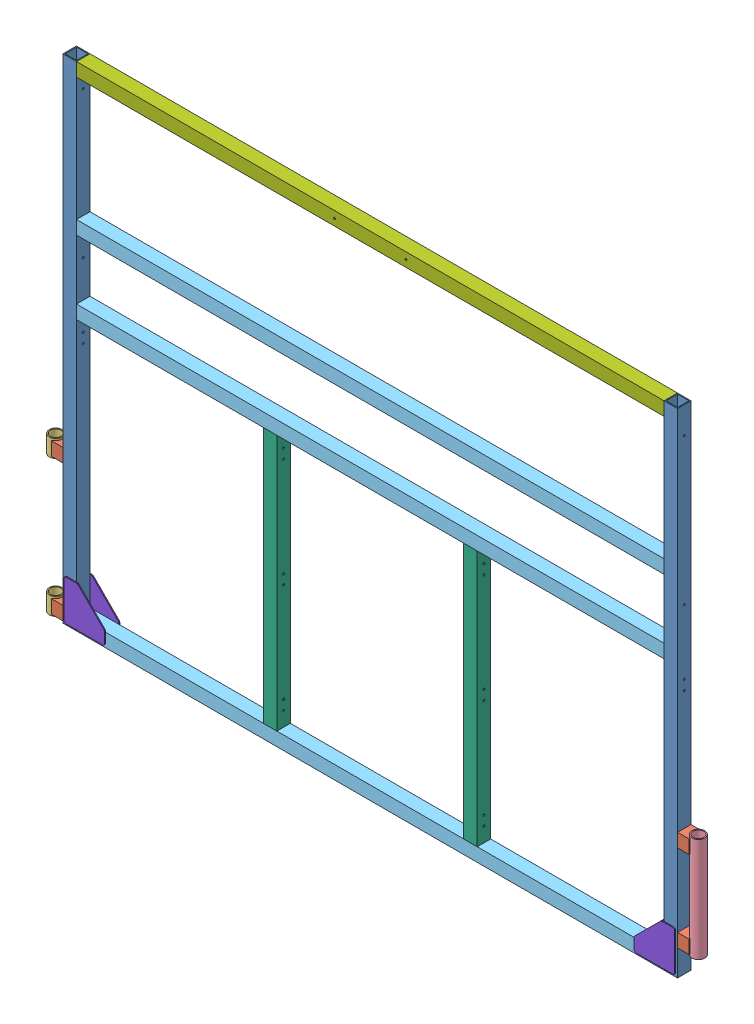
SolidWorks assembly GE-25001, configuration Default. Lengths in mm.
Overall size (2163.1 1625.6 50.8).
19 component instances, 8 part files, 45 mates.
Components (placement in the parent):
- GE-25001-01-1: GE-25001-01 [Default] at (-1012.825 1625.6 -22.225) x (0 -1 0) z (-1 0 0) size (1625.6 44.45 44.45)
- GE-25001-04-1: GE-25001-04 [Default] at (-1012.825 50.8 -22.225) x (-1 0 0) z (0 1 0) size (38.1 44.45 44.45)
- GE-25001-05-2: GE-25001-05 [Default] at (-1059.307 450.85 0) x (0.99576 0 -0.091988) z (0.091988 0 0.99576) size (42.16 57.15 42.16)
- GE-25001-04-2: GE-25001-04 [Default] at (-1012.825 501.65 -22.225) x (-1 0 0) z (0 1 0) size (38.1 44.45 44.45)
- GE-25001-01-2: GE-25001-01 [Default] at (968.375 1625.6 -22.225) x (0 -1 0) z (-1 0 0) size (1625.6 44.45 44.45)
- GE-25001-04-3: GE-25001-04 [Default] at (1012.825 130.175 22.225) x (1 0 0) z (0 1 0) size (38.1 44.45 44.45)
- GE-25001-04-4: GE-25001-04 [Default] at (1012.825 415.925 22.225) x (1 0 0) z (0 1 0) size (38.1 44.45 44.45)
- GE-25001-06-1: GE-25001-06 [Default] at (1059.307 79.375 0) x (-0.999745 0 0.022564) z (-0.022564 0 -0.999745) size (42.16 342.9 42.16)
- GE-25001-03-1: GE-25001-03 [Default] at (-968.375 889 22.225) size (1936.75 44.45 44.45)
- GE-25001-03-2: GE-25001-03 [Default] at (-968.375 0 22.225) size (1936.75 44.45 44.45)
- GE-25001-03-4: GE-25001-03 [Default] at (-968.375 1130.3 22.225) size (1936.75 44.45 44.45)
- GE-25001-02-1: GE-25001-02 [Default] at (-352.425 44.45 -22.225) x (0 0 1) z (-1 0 0) size (44.45 844.55 44.45)
- GE-25001-02-2: GE-25001-02 [Default] at (307.975 44.45 -22.225) x (0 0 1) z (-1 0 0) size (44.45 844.55 44.45)
- GE-25001-05-3: GE-25001-05 [Default] at (-1059.307 0 0) x (-1 0 0) z (0 0 -1) size (42.16 57.15 42.16)
- GE-25001-07-1: GE-25001-07 [Default] at (-968.375 1581.15 22.225) size (1936.75 44.45 44.45)
- GE-25001-08-1: GE-25001-08 [Default] at (1006.475 6.35 -25.4) x (0 1 0) z (1 0 0) size (133.35 3.17 133.35)
- GE-25001-08-2: GE-25001-08 [Default] at (1006.475 6.35 22.225) x (0 1 0) z (1 0 0) size (133.35 3.17 133.35)
- GE-25001-08-3: GE-25001-08 [Default] at (-1006.475 6.35 -22.225) x (0 1 0) z (-1 0 0) size (133.35 3.17 133.35)
- GE-25001-08-4: GE-25001-08 [Default] at (-1006.475 6.35 25.4) x (0 1 0) z (-1 0 0) size (133.35 3.17 133.35)
Mates (geometry in assembly coordinates):
- Coincident4: coincident aligned: plane of GE-24001-01-1 through (-1012.825 0 22.225) normal (0 0 1); plane of GE-24001-04-1 through (-1050.925 50.8 22.225) normal (0 0 1)
- Distance1: distance = 6.35 mm aligned: plane of Front Frame Pin Holders-1 through (-1050.925 6.35 -22.225) normal (0 -1 0); plane of GE-24001-01-1 through (-1012.825 0 -22.225) normal (0 -1 0)
- Coincident6: coincident anti-aligned: plane of GE-24001-01-1 through (-1012.825 0 -22.225) normal (-1 0 0); plane of GE-24001-04-1 through (-1012.825 50.8 -22.225) normal (1 0 0)
- Coincident9: coincident aligned: plane of GE-24001-04-1 through (-1050.925 50.8 22.225) normal (0 0 1); plane of GE-24001-04-2 through (-1050.925 501.65 22.225) normal (0 0 1)
- Coincident10: coincident anti-aligned: plane of GE-24001-01-1 through (-1012.825 0 -22.225) normal (-1 0 0); plane of GE-24001-04-2 through (-1012.825 501.65 -22.225) normal (1 0 0)
- Coincident12: coincident aligned: plane of GE-24001-01-1 through (-1012.825 0 22.225) normal (0 0 1); plane of GE-24001-01-2 through (968.375 0 22.225) normal (0 0 1)
- Coincident13: coincident aligned: plane of GE-24001-01-1 through (-1012.825 1625.6 -22.225) normal (0 1 0); plane of GE-24001-01-2 through (968.375 1625.6 -22.225) normal (0 1 0)
- Coincident14: coincident aligned: plane of GE-24001-01-2 through (968.375 0 -22.225) normal (0 0 -1); plane of GE-24001-04-4 through (1050.925 415.925 -22.225) normal (0 0 -1)
- Coincident15: coincident anti-aligned: plane of GE-24001-01-2 through (1012.825 0 -22.225) normal (1 0 0); plane of GE-24001-04-4 through (1012.825 415.925 22.225) normal (-1 0 0)
- Coincident16: coincident anti-aligned: plane of GE-24001-01-2 through (1012.825 0 -22.225) normal (1 0 0); plane of GE-24001-04-3 through (1012.825 130.175 22.225) normal (-1 0 0)
- Coincident18: coincident aligned: plane of GE-24001-04-3 through (1050.925 130.175 22.225) normal (0 0 1); plane of GE-24001-04-4 through (1050.925 415.925 22.225) normal (0 0 1)
- Distance4: distance = 79.375 mm aligned: plane of GE-24001-01-2 through (968.375 0 -22.225) normal (0 -1 0); plane of GE-24001-06-1 through (1059.307 79.375 0) normal (0 -1 0)
- Distance5: distance = 6.35 mm aligned: plane of Front Frame Pin Holders-3 through (1050.925 85.725 22.225) normal (0 -1 0); plane of GE-24001-06-1 through (1059.307 79.375 0) normal (0 -1 0)
- Concentric3: concentric anti-aligned: cylinder of GE-24001-04-3 through (1059.307 85.725 0) axis (0 1 0) radius 21.082; cylinder of GE-24001-06-1 through (1059.307 422.275 0) axis (0 -1 0) radius 21.082
- Distance6: distance = 6.35 mm aligned: plane of Front Frame Pin Holders-4 through (1050.925 415.925 22.225) normal (0 1 0); plane of GE-24001-06-1 through (1059.307 422.275 0) normal (0 1 0)
- Coincident22: coincident aligned: plane of GE-24001-03-1 through (968.375 889 22.225) normal (0 0 1); plane of GE-24001-03-4 through (968.375 1130.3 22.225) normal (0 0 1)
- Coincident25: coincident aligned: plane of GE-24001-01-1 through (-1012.825 0 22.225) normal (0 0 1); plane of GE-24001-03-2 through (968.375 0 22.225) normal (0 0 1)
- Coincident26: coincident aligned: plane of GE-24001-01-1 through (-1012.825 0 -22.225) normal (0 -1 0); plane of GE-24001-03-2 through (968.375 0 22.225) normal (0 -1 0)
- Coincident27: coincident anti-aligned: plane of GE-24001-01-1 through (-968.375 0 -22.225) normal (1 0 0); plane of GE-24001-03-2 through (-968.375 0 22.225) normal (-1 0 0)
- Coincident28: coincident anti-aligned: plane of GE-24001-01-2 through (968.375 0 -22.225) normal (-1 0 0); plane of GE-24001-03-2 through (968.375 0 22.225) normal (1 0 0)
- Coincident32: coincident anti-aligned: plane of GE-24001-01-1 through (-968.375 0 -22.225) normal (1 0 0); plane of GE-24001-03-4 through (-968.375 1130.3 22.225) normal (-1 0 0)
- Coincident33: coincident anti-aligned: plane of GE-24001-01-1 through (-968.375 0 -22.225) normal (1 0 0); plane of GE-24001-03-1 through (-968.375 889 22.225) normal (-1 0 0)
- Distance8: distance = 933.45 mm anti-aligned: plane of GE-24001-03-1 through (968.375 933.45 22.225) normal (0 1 0); plane of GE-24001-03-2 through (968.375 0 22.225) normal (0 -1 0)
- Distance9: distance = 196.85 mm anti-aligned: plane of GE-24001-03-4 through (968.375 1130.3 22.225) normal (0 -1 0); plane of GE-24001-03-1 through (968.375 933.45 22.225) normal (0 1 0)
- Coincident40: coincident anti-aligned: plane of GE-24001-03-1 through (968.375 889 22.225) normal (0 -1 0); plane of GE-24001-02-2 through (307.975 889 -22.225) normal (0 1 0)
- Coincident41: coincident aligned: plane of GE-24001-03-1 through (968.375 889 22.225) normal (0 0 1); plane of GE-24001-02-1 through (-352.425 889 22.225) normal (0 0 1)
- Coincident42: coincident anti-aligned: plane of GE-24001-03-1 through (968.375 889 22.225) normal (0 -1 0); plane of GE-24001-02-1 through (-352.425 889 -22.225) normal (0 1 0)
- Distance12: distance = 615.95 mm anti-aligned: plane of GE-24001-01-1 through (-968.375 0 -22.225) normal (1 0 0); plane of Front Frame Inner Vertical-1 through (-352.425 889 -22.225) normal (-1 0 0)
- Coincident45: coincident aligned: plane of GE-24001-03-1 through (968.375 889 22.225) normal (0 0 1); plane of GE-24001-02-2 through (307.975 889 22.225) normal (0 0 1)
- Distance13: distance = 615.95 mm anti-aligned: plane of Front Frame Inner Vertical-2 through (352.425 889 -22.225) normal (1 0 0); plane of GE-24001-01-2 through (968.375 0 -22.225) normal (-1 0 0)
- Concentric4: concentric anti-aligned: cylinder of GE-24001-04-1 through (-1059.307 6.35 0) axis (0 1 0) radius 21.082; cylinder of GE-24001-05-3 through (-1059.307 57.15 0) axis (0 -1 0) radius 21.082
- Distance14: distance = 6.35 mm aligned: plane of Front Frame Small Pin Shell-3 through (-1059.307 0 0) normal (0 -1 0); plane of Front Frame Pin Holders-1 through (-1050.925 6.35 -22.225) normal (0 -1 0)
- Concentric5: concentric anti-aligned: cylinder of GE-24001-05-2 through (-1059.307 508 0) axis (0 -1 0) radius 21.082; cylinder of GE-24001-04-2 through (-1059.307 457.2 0) axis (0 1 0) radius 21.082
- Distance15: distance = 393.7 mm anti-aligned: plane of Front Frame Small Pin Shell-2 through (-1059.307 450.85 0) normal (0 -1 0); plane of Front Frame Small Pin Shell-3 through (-1059.307 57.15 0) normal (0 1 0)
- Distance16: distance = 6.35 mm aligned: plane of Front Frame Small Pin Shell-2 through (-1059.307 508 0) normal (0 1 0); plane of Front Frame Pin Holders-2 through (-1050.925 501.65 -22.225) normal (0 1 0)
- Coincident46: coincident anti-aligned: plane of GE-24001-03-2 through (968.375 0 22.225) normal (0 -1 0)
- Symmetric1: symmetric aligned: plane of GE-24001-01-1 through (-1012.825 0 -22.225) normal (-1 0 0); plane of GE-24001-01-2 through (1012.825 0 -22.225) normal (1 0 0)
- Coincident47: coincident anti-aligned: plane of GE-24001-01-1 through (-968.375 0 -22.225) normal (1 0 0); plane of GE-24001-07-1 through (-968.375 1581.15 22.225) normal (-1 0 0)
- Coincident48: coincident aligned: plane of GE-24001-01-1 through (-1012.825 0 -22.225) normal (0 0 -1); plane of GE-24001-07-1 through (968.375 1581.15 -22.225) normal (0 0 -1)
- Coincident49: coincident aligned: plane of GE-24001-01-1 through (-1012.825 1625.6 -22.225) normal (0 1 0); plane of GE-24001-07-1 through (968.375 1625.6 22.225) normal (0 1 0)
- Coincident50: coincident aligned: plane of GE-24001-01-1 through (-1012.825 0 -22.225) normal (0 0 -1); plane of GE-24001-03-4 through (968.375 1130.3 -22.225) normal (0 0 -1)
- Symmetric2: symmetric aligned: plane of GE-24001-07-1 through (968.375 1581.15 -22.225) normal (0 0 -1); plane of GE-24001-07-1 through (968.375 1581.15 22.225) normal (0 0 1)
- Coincident51: coincident anti-aligned: plane of GE-24001-01-2 through (968.375 0 -22.225) normal (0 0 -1); plane of Corner Gusset-1 through (1012.825 6.35 -22.225) normal (0 0 1)
- Distance17: distance = 6.35 mm aligned: plane of GE-25001-03-2 through (968.375 0 22.225) normal (0 -1 0); plane of GE-25001-08-1 through (1006.475 6.35 -22.225) normal (0 -1 0)
- Distance18: distance = 6.35 mm aligned: plane of GE-25001-01-2 through (1012.825 0 -22.225) normal (1 0 0); plane of GE-25001-08-1 through (1006.475 139.7 -22.225) normal (1 0 0)
